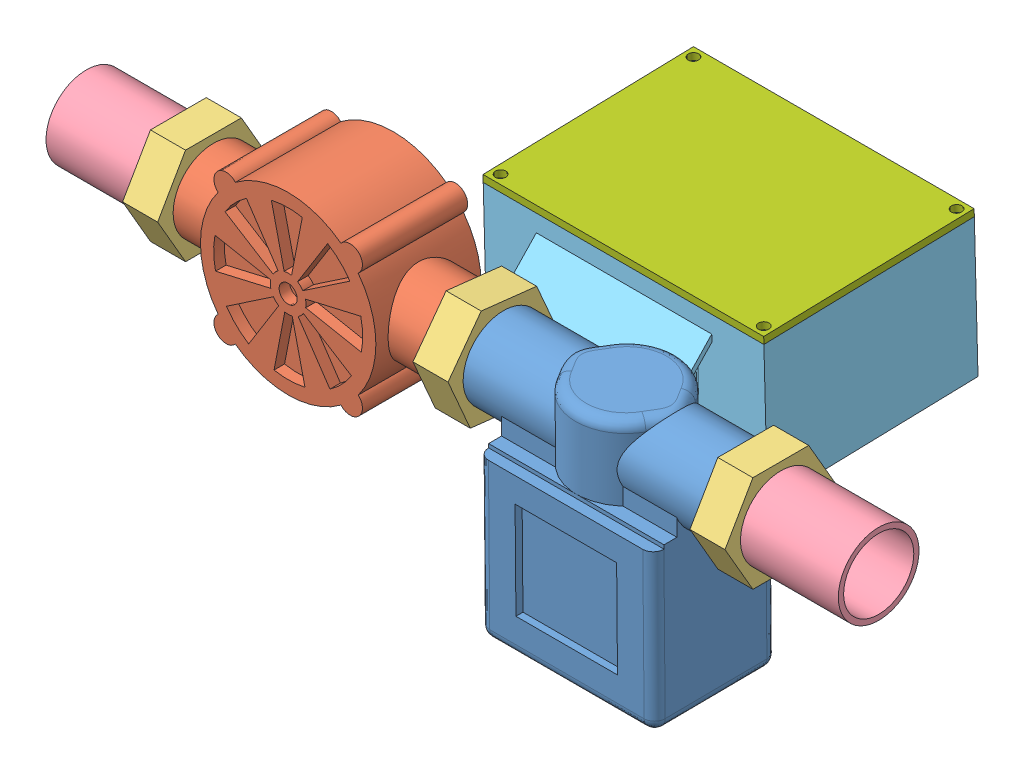
SolidWorks assembly sistema, configuration Predeterminado. Lengths in mm.
Overall size (225.84 80.15 124.41).
11 component instances, 7 part files, 6 mates.
Components (placement in the parent):
- valvula de agua-1: valvula de agua [Predeterminado] at (-50.6637 26.5798 0.3074) x (1 0 0) z (0 -0.999962 -0.008727) size (80 35 67.07)
- sensor de flujo-1: sensor de flujo [Predeterminado] at (-132.1637 36.5794 0.3946) x (1 0 0) z (0 0 -1) size (83 50 31)
- tuerca-1: tuerca [Predeterminado] at (-168.4528 36.5794 0.3946) x (0 0 1) z (-1 0 0) size (31.82 27.57 10)
- tuerca-2: tuerca [Predeterminado] at (-85.7899 36.5794 0.3946) x (0 0.113203 0.993572) z (-1 0 0) size (31.82 27.57 10)
- tuerca-3: tuerca [Predeterminado] at (-6.7422 36.5794 0.3946) x (0 0 1) z (-1 0 0) size (31.82 27.57 10)
- tubo de media-1: tubo de media [Predeterminado] at (6.1516 36.5794 0.3946) x (0 0 -1) z (1 0 0) size (23 23 30)
- tubo de media-2: tubo de media [Predeterminado] at (-189.6874 36.5794 0.3946) x (0 0 1) z (-1 0 0) size (23 23 30)
- ensamble de caja-1: ensamble de caja [Predeterminado] at (-119.8623 23.7642 -73.5442) x (1 0 0) z (0 0.999657 0.026177) size (81.33 79.56 42)
  - proyecto case-1: proyecto case [Predeterminado] at (32.2877 -7.4744 -21.9408) size (80 79.56 40)
  - conector-1: conector [Predeterminado] at (-6.0431 -27.4744 -11.9408) x (0 0 1) z (-1 0 0) size (7 7 3)
  - tapadera de case-1: tapadera de case [Predeterminado] at (32.2877 -7.4744 18.0592) x (0 1 0) z (0 0 1) size (60 80 2)
Mates (geometry in assembly coordinates):
- Coincidente1: coincident aligned: circle of valvula de agua-1; circle of sensor de flujo-1
- Concéntrica1: concentric anti-aligned: circle of sensor de flujo-1; circle of tuerca-2
- Concéntrica2: concentric anti-aligned: circle of valvula de agua-1; circle of tuerca-3
- Concéntrica3: concentric anti-aligned: circle of sensor de flujo-1; circle of tuerca-1
- Concéntrica4: concentric aligned: circle of valvula de agua-1; circle of tubo de media-1
- Concéntrica5: concentric anti-aligned: circle of sensor de flujo-1; circle of tubo de media-2
